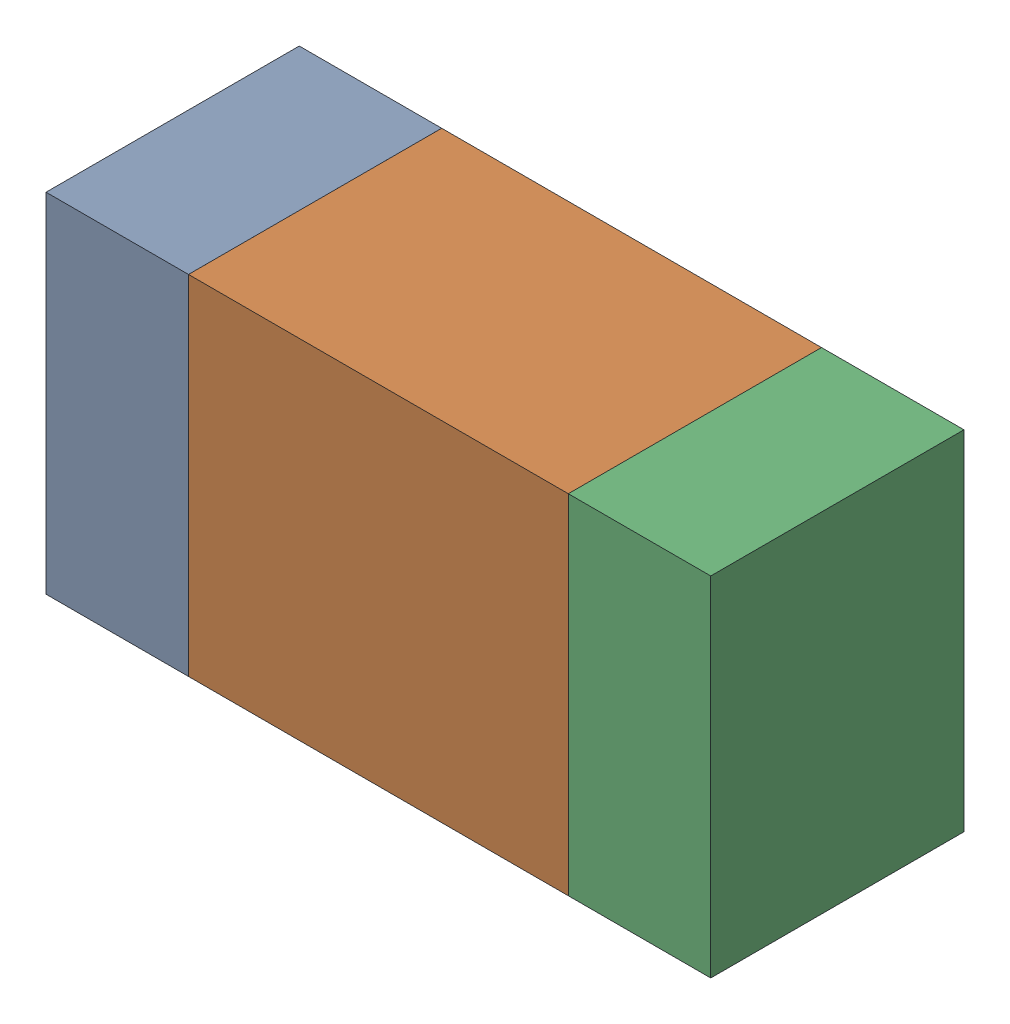
SolidWorks assembly R501_1PCB, configuration Default. Lengths in mm.
Overall size (1.05 0.55 0.4).
6 component instances, 2 part files, 0 mates.
Components (placement in the parent):
- 854785432-1: 854785432 [Default] at (156.2376 116.7501 0) size (0.22 0.55 0.4)
  - Extruded-1: Extruded [Default] at origin size (0.22 0.55 0.4)
- 854785568-1: 854785568 [Default] at (156.6501 116.7501 0) size (0.6 0.55 0.4)
  - Extruded_2-1: Extruded_2 [Default] at origin size (0.6 0.55 0.4)
- 854785432-2: 854785432 [Default] at (157.0626 116.7501 0) size (0.22 0.55 0.4)
  - Extruded-1: Extruded [Default] at origin size (0.22 0.55 0.4)
